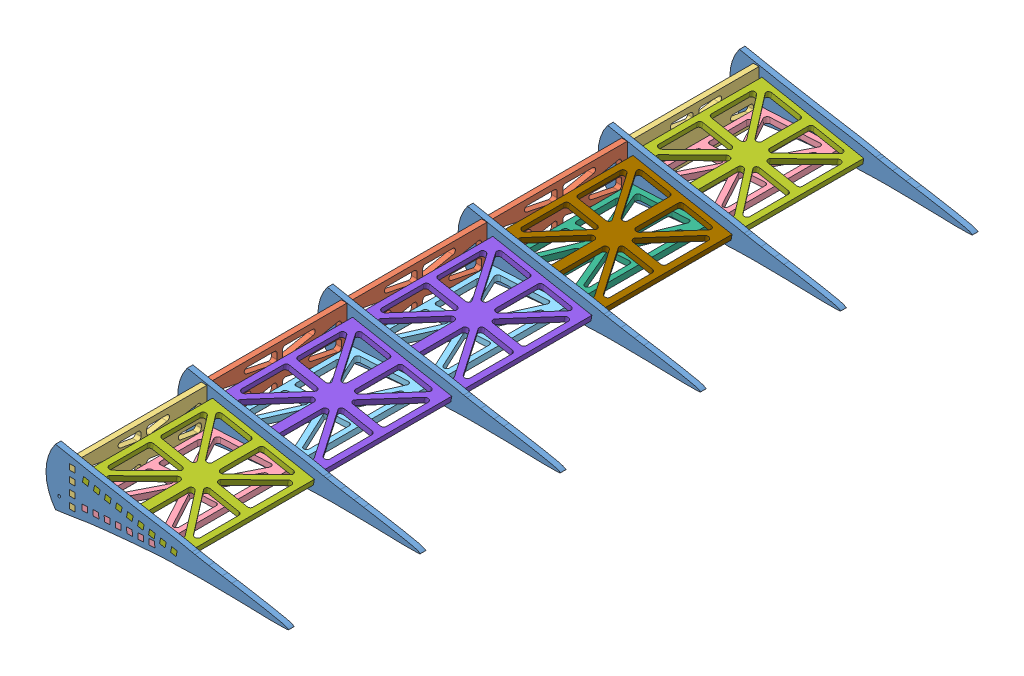
SolidWorks assembly eleron, configuration Default. Lengths in mm.
Overall size (569.01 68.52 550.19).
21 component instances, 9 part files, 60 mates.
Components (placement in the parent):
- eleron_2-1: eleron_2 [Default] at (-99.8109 340.0461 432.4924) size (569.01 68.52 62.19)
- eleron_2-2: eleron_2 [Default] at (-99.8109 340.0461 826.4924) size (569.01 68.52 62.19)
- vertical_eleron_96mm-1: vertical_eleron_96mm [Default] at (316.8476 362.3289 674.4924) x (0 0 -1) z (0 -1 0) size (104 4 35.61)
- eleron_2-3: eleron_2 [Default] at (-99.8109 340.0461 626.4924) size (569.01 68.52 62.19)
- eleron_2-4: eleron_2 [Default] at (-99.8109 340.0461 526.4924) size (569.01 68.52 62.19)
- eleron_2-5: eleron_2 [Default] at (-99.8109 340.0461 920.4924) size (569.01 68.52 62.19)
- eleron_2-6: eleron_2 [Default] at (-99.8109 340.0461 726.4924) size (569.01 68.52 62.19)
- vertical_eleron_90mm-1: vertical_eleron_90mm [Default] at (316.8476 360.3289 902.9685) x (0 0 -1) z (0 -1 0) size (98 4 34.76)
- vertical_eleron_96mm-2: vertical_eleron_96mm [Default] at (316.8476 362.3289 574.4924) x (0 0 -1) z (0 -1 0) size (104 4 35.61)
- vertical_eleron_96mm-3: vertical_eleron_96mm [Default] at (316.8476 362.3289 474.4924) x (0 0 -1) z (0 -1 0) size (104 4 35.61)
- vertical_eleron_90mm-2: vertical_eleron_90mm [Default] at (316.8476 364.3289 446.0162) x (0 0 1) z (0 1 0) size (98 4 34.76)
- orizontala_eleron_90mm_7_gauri-1: orizontala_eleron_90mm_7_gauri [Default] at (332.9244 356.4588 906.0924) x (0 0 -1) z (0.998562 0.053604 0) size (98 4 58)
- orizontala_eleron_96mm_7_gauri-1: orizontala_eleron_96mm_7_gauri [Default] at (361.5332 357.9945 744.2066) x (0 0 1) z (-0.998562 -0.053604 0) size (104 4 56)
- orizontala_eleron_96mm_7_gauri-2: orizontala_eleron_96mm_7_gauri [Default] at (361.5332 357.9945 644.2066) x (0 0 1) z (-0.998562 -0.053604 0) size (104 4 56)
- orizontala_eleron_90mm_7_gauri-2: orizontala_eleron_90mm_7_gauri [Default] at (362.1823 358.0294 442.8924) x (0 0 1) z (-0.998562 -0.053604 0) size (98 4 58)
- orizontala_eleron_96mm_7_gauri_2-1: orizontala_eleron_96mm_7_gauri_2 [Default] at (361.5332 357.9945 544.2066) x (0 0 1) z (-0.998562 -0.053604 0) size (104 4 56)
- orizontala_eleron_90mm_9_gauri-1: orizontala_eleron_90mm_9_gauri [Default] at (333.9983 371.3057 906.0924) x (0 0 -1) z (0.98244 -0.18658 0) size (98 4 74)
- orizontala_eleron_96mm_9_gauri-1: orizontala_eleron_96mm_9_gauri [Default] at (377.8643 362.9749 744.2066) x (0 0 1) z (-0.98244 0.18658 0) size (104 4 72)
- orizontala_eleron_90mm_9_gauri-2: orizontala_eleron_90mm_9_gauri [Default] at (378.5029 362.8536 442.8924) x (0 0 1) z (-0.98244 0.18658 0) size (98 4 74)
- orizontala_eleron_96mm_9_gauri-2: orizontala_eleron_96mm_9_gauri [Default] at (377.8643 362.9749 644.2066) x (0 0 1) z (-0.98244 0.18658 0) size (104 4 72)
- orizontala_eleron_96mm_9_gauri_2-1: orizontala_eleron_96mm_9_gauri_2 [Default] at (334.6369 371.1844 604.7781) x (0 0 -1) z (0.98244 -0.18658 0) size (104 4 72)
Mates (geometry in assembly coordinates):
- Concentric2: concentric aligned: circle of eleron_2-1; circle of eleron_2-2
- Concentric3: concentric aligned: circle of eleron_2-1; circle of eleron_2-3
- Concentric4: concentric aligned: circle of eleron_2-1; circle of eleron_2-4
- Concentric5: concentric aligned: circle of eleron_2-1; circle of eleron_2-5
- Concentric6: concentric aligned: circle of eleron_2-1; circle of eleron_2-6
- Parallel1: parallel aligned: line of eleron_2-5 through (400.3332 336.2444 920.4924) axis (0 1 0); line of eleron_2-6 through (400.3332 336.2444 726.4924) axis (0 1 0)
- Parallel2: parallel aligned: line of eleron_2-5 through (400.3332 336.2444 920.4924) axis (0 1 0); line of eleron_2-2 through (400.3332 336.2444 826.4924) axis (0 1 0)
- Parallel3: parallel aligned: line of eleron_2-5 through (400.3332 336.2444 920.4924) axis (0 1 0); line of eleron_2-3 through (400.3332 336.2444 626.4924) axis (0 1 0)
- Parallel4: parallel aligned: line of eleron_2-5 through (400.3332 336.2444 920.4924) axis (0 1 0); line of eleron_2-4 through (400.3332 336.2444 526.4924) axis (0 1 0)
- Parallel5: parallel aligned: line of eleron_2-5 through (400.3332 336.2444 920.4924) axis (0 1 0); line of eleron_2-1 through (400.3332 336.2444 432.4924) axis (0 1 0)
- Distance1: distance = 90 mm anti-aligned: plane of eleron_2-5 through (-99.8109 340.0461 916.4924) normal (0 0 -1); plane of eleron_2-2 through (-99.8109 340.0461 826.4924) normal (0 0 1)
- Distance2: distance = 96 mm anti-aligned: plane of eleron_2-2 through (-99.8109 340.0461 822.4924) normal (0 0 -1); plane of eleron_2-6 through (-99.8109 340.0461 726.4924) normal (0 0 1)
- Distance3: distance = 96 mm anti-aligned: plane of eleron_2-6 through (-99.8109 340.0461 722.4924) normal (0 0 -1); plane of eleron_2-3 through (-99.8109 340.0461 626.4924) normal (0 0 1)
- Distance4: distance = 96 mm anti-aligned: plane of eleron_2-4 through (-99.8109 340.0461 526.4924) normal (0 0 1); plane of eleron_2-3 through (-99.8109 340.0461 622.4924) normal (0 0 -1)
- Distance5: distance = 90 mm anti-aligned: plane of eleron_2-4 through (-99.8109 340.0461 522.4924) normal (0 0 -1); plane of eleron_2-1 through (-99.8109 340.0461 432.4924) normal (0 0 1)
- Coincident23: coincident aligned: plane of eleron_2-5 through (-99.8109 340.0461 920.4924) normal (0 0 1); plane of vertical_eleron_90mm-1 through (312.8476 368.3289 920.4924) normal (0 0 1)
- Coincident24: coincident anti-aligned: plane of eleron_2-5 through (312.8476 376.3289 916.4924) normal (0 -1 0); plane of vertical_eleron_90mm-1 through (312.8476 376.3289 916.4924) normal (0 1 0)
- Coincident25: coincident anti-aligned: plane of eleron_2-5 through (316.8476 376.3289 916.4924) normal (-1 0 0); plane of vertical_eleron_90mm-1 through (316.8476 360.3289 902.9685) normal (1 0 0)
- Coincident26: coincident anti-aligned: plane of eleron_2-2 through (-99.8109 340.0461 822.4924) normal (0 0 -1); plane of vertical_eleron_96mm-1 through (312.8476 380.5589 822.4924) normal (0 0 1)
- Coincident27: coincident anti-aligned: plane of eleron_2-2 through (312.8476 348.3289 822.4924) normal (0 1 0); plane of vertical_eleron_96mm-1 through (312.8476 348.3289 826.4924) normal (0 -1 0)
- Coincident28: coincident anti-aligned: plane of eleron_2-2 through (316.8476 368.3289 822.4924) normal (-1 0 0); plane of vertical_eleron_96mm-1 through (316.8476 362.3289 674.4924) normal (1 0 0)
- Coincident29: coincident anti-aligned: plane of eleron_2-6 through (316.8476 352.3289 722.4924) normal (-1 0 0); plane of vertical_eleron_96mm-2 through (316.8476 362.3289 574.4924) normal (1 0 0)
- Coincident30: coincident anti-aligned: plane of eleron_2-6 through (312.8476 348.3289 722.4924) normal (0 1 0); plane of vertical_eleron_96mm-2 through (312.8476 348.3289 726.4924) normal (0 -1 0)
- Coincident31: coincident anti-aligned: plane of eleron_2-6 through (-99.8109 340.0461 722.4924) normal (0 0 -1); plane of vertical_eleron_96mm-2 through (312.8476 380.5589 722.4924) normal (0 0 1)
- Coincident32: coincident anti-aligned: plane of eleron_2-3 through (-99.8109 340.0461 622.4924) normal (0 0 -1); plane of vertical_eleron_96mm-3 through (312.8476 380.5589 622.4924) normal (0 0 1)
- Coincident33: coincident anti-aligned: plane of eleron_2-3 through (312.8476 348.3289 622.4924) normal (0 1 0); plane of vertical_eleron_96mm-3 through (312.8476 348.3289 626.4924) normal (0 -1 0)
- Coincident34: coincident anti-aligned: plane of eleron_2-3 through (316.8476 352.3289 622.4924) normal (-1 0 0); plane of vertical_eleron_96mm-3 through (316.8476 362.3289 474.4924) normal (1 0 0)
- Coincident35: coincident anti-aligned: plane of eleron_2-4 through (-99.8109 340.0461 522.4924) normal (0 0 -1); plane of vertical_eleron_90mm-2 through (312.8476 352.3289 522.4924) normal (0 0 1)
- Coincident36: coincident anti-aligned: plane of eleron_2-4 through (312.8476 348.3289 522.4924) normal (0 1 0); plane of vertical_eleron_90mm-2 through (312.8476 348.3289 522.4924) normal (0 -1 0)
- Coincident37: coincident anti-aligned: plane of eleron_2-4 through (316.8476 368.3289 522.4924) normal (-1 0 0); plane of vertical_eleron_90mm-2 through (316.8476 364.3289 446.0162) normal (1 0 0)
- Coincident38: coincident anti-aligned: plane of eleron_2-5 through (-99.8109 340.0461 916.4924) normal (0 0 -1); plane of orizontala_eleron_90mm_7_gauri-1 through (365.7419 354.2147 916.4924) normal (0 0 1)
- Coincident39: coincident anti-aligned: plane of eleron_2-5 through (373.516 358.6378 916.4924) normal (-0.998562 -0.053604 0); plane of orizontala_eleron_90mm_7_gauri-1 through (373.7304 354.6435 920.4924) normal (0.998562 0.053604 0)
- Coincident40: coincident anti-aligned: plane of eleron_2-5 through (369.5217 358.4234 916.4924) normal (0.053604 -0.998562 0); plane of orizontala_eleron_90mm_7_gauri-1 through (332.9244 356.4588 906.0924) normal (-0.053604 0.998562 0)
- Coincident41: coincident anti-aligned: plane of eleron_2-2 through (-99.8109 340.0461 822.4924) normal (0 0 -1); plane of orizontala_eleron_96mm_7_gauri-1 through (319.808 351.7489 822.4924) normal (0 0 1)
- Coincident42: coincident anti-aligned: plane of eleron_2-2 through (361.5332 357.9945 822.4924) normal (0.053604 -0.998562 0); plane of orizontala_eleron_96mm_7_gauri-1 through (361.5332 357.9945 744.2066) normal (-0.053604 0.998562 0)
- Coincident43: coincident anti-aligned: plane of eleron_2-2 through (365.5275 358.209 822.4924) normal (-0.998562 -0.053604 0); plane of orizontala_eleron_96mm_7_gauri-1 through (365.7419 354.2147 822.4924) normal (0.998562 0.053604 0)
- Coincident44: coincident anti-aligned: plane of eleron_2-6 through (-99.8109 340.0461 722.4924) normal (0 0 -1); plane of orizontala_eleron_96mm_7_gauri-2 through (375.7275 354.7507 722.4924) normal (0 0 1)
- Coincident45: coincident anti-aligned: plane of eleron_2-6 through (361.5332 357.9945 722.4924) normal (0.053604 -0.998562 0); plane of orizontala_eleron_96mm_7_gauri-2 through (361.5332 357.9945 644.2066) normal (-0.053604 0.998562 0)
- Coincident46: coincident anti-aligned: plane of eleron_2-6 through (365.5275 358.209 722.4924) normal (-0.998562 -0.053604 0); plane of orizontala_eleron_96mm_7_gauri-2 through (365.7419 354.2147 722.4924) normal (0.998562 0.053604 0)
- Coincident51: coincident anti-aligned: plane of eleron_2-3 through (-99.8109 340.0461 622.4924) normal (0 0 -1); plane of orizontala_eleron_96mm_7_gauri_2-1 through (319.808 351.7489 622.4924) normal (0 0 1)
- Coincident52: coincident anti-aligned: plane of eleron_2-3 through (365.5275 358.209 622.4924) normal (-0.998562 -0.053604 0); plane of orizontala_eleron_96mm_7_gauri_2-1 through (365.7419 354.2147 622.4924) normal (0.998562 0.053604 0)
- Coincident54: coincident anti-aligned: plane of eleron_2-3 through (361.5332 357.9945 622.4924) normal (0.053604 -0.998562 0); plane of orizontala_eleron_96mm_7_gauri_2-1 through (361.5332 357.9945 544.2066) normal (-0.053604 0.998562 0)
- Coincident55: coincident anti-aligned: plane of eleron_2-4 through (337.5677 356.708 522.4924) normal (0.053604 -0.998562 0); plane of orizontala_eleron_90mm_7_gauri-2 through (362.1823 358.0294 442.8924) normal (-0.053604 0.998562 0)
- Coincident56: coincident anti-aligned: plane of eleron_2-4 through (-99.8109 340.0461 522.4924) normal (0 0 -1); plane of orizontala_eleron_90mm_7_gauri-2 through (369.7362 354.4291 522.4924) normal (0 0 1)
- Coincident57: coincident anti-aligned: plane of eleron_2-4 through (321.8052 351.8561 522.4924) normal (0.998562 0.053604 0); plane of orizontala_eleron_90mm_7_gauri-2 through (321.8052 351.8561 526.4924) normal (-0.998562 -0.053604 0)
- Coincident58: coincident anti-aligned: plane of eleron_2-5 through (-99.8109 340.0461 916.4924) normal (0 0 -1); plane of orizontala_eleron_90mm_9_gauri-1 through (326.0311 368.7473 916.4924) normal (0 0 1)
- Coincident59: coincident anti-aligned: plane of eleron_2-5 through (388.9072 356.8062 916.4924) normal (-0.98244 0.18658 0); plane of orizontala_eleron_90mm_9_gauri-1 through (388.9072 356.8062 920.4924) normal (0.98244 -0.18658 0)
- Coincident60: coincident anti-aligned: plane of eleron_2-5 through (389.6536 360.7359 916.4924) normal (-0.18658 -0.98244 0); plane of orizontala_eleron_90mm_9_gauri-1 through (333.9983 371.3057 906.0924) normal (0.18658 0.98244 0)
- Coincident61: coincident anti-aligned: plane of eleron_2-2 through (-99.8109 340.0461 822.4924) normal (0 0 -1); plane of orizontala_eleron_96mm_9_gauri-1 through (345.6799 365.0157 822.4924) normal (0 0 1)
- Coincident62: coincident anti-aligned: plane of eleron_2-2 through (381.0477 358.2988 822.4924) normal (-0.98244 0.18658 0); plane of orizontala_eleron_96mm_9_gauri-1 through (381.0477 358.2988 822.4924) normal (0.98244 -0.18658 0)
- Coincident63: coincident anti-aligned: plane of eleron_2-2 through (381.794 362.2286 822.4924) normal (-0.18658 -0.98244 0); plane of orizontala_eleron_96mm_9_gauri-1 through (377.8643 362.9749 744.2066) normal (0.18658 0.98244 0)
- Coincident67: coincident anti-aligned: plane of eleron_2-1 through (-99.8109 340.0461 432.4924) normal (0 0 1); plane of orizontala_eleron_90mm_9_gauri-2 through (322.1013 369.4936 432.4924) normal (0 0 -1)
- Coincident68: coincident anti-aligned: plane of eleron_2-1 through (388.9072 356.8062 428.4924) normal (-0.98244 0.18658 0); plane of orizontala_eleron_90mm_9_gauri-2 through (388.9072 356.8062 432.4924) normal (0.98244 -0.18658 0)
- Coincident69: coincident anti-aligned: plane of eleron_2-1 through (389.6536 360.7359 428.4924) normal (-0.18658 -0.98244 0); plane of orizontala_eleron_90mm_9_gauri-2 through (378.5029 362.8536 442.8924) normal (0.18658 0.98244 0)
- Coincident70: coincident anti-aligned: plane of eleron_2-6 through (381.794 362.2286 722.4924) normal (-0.18658 -0.98244 0); plane of orizontala_eleron_96mm_9_gauri-2 through (377.8643 362.9749 644.2066) normal (0.18658 0.98244 0)
- Coincident73: coincident anti-aligned: plane of eleron_2-6 through (-99.8109 340.0461 722.4924) normal (0 0 -1); plane of orizontala_eleron_96mm_9_gauri-2 through (361.3989 362.0304 722.4924) normal (0 0 1)
- Coincident74: coincident anti-aligned: plane of eleron_2-6 through (381.0477 358.2988 722.4924) normal (-0.98244 0.18658 0); plane of orizontala_eleron_96mm_9_gauri-2 through (381.0477 358.2988 722.4924) normal (0.98244 -0.18658 0)
- Coincident75: coincident anti-aligned: plane of eleron_2-3 through (381.794 362.2286 622.4924) normal (-0.18658 -0.98244 0); plane of orizontala_eleron_96mm_9_gauri_2-1 through (334.6369 371.1844 604.7781) normal (0.18658 0.98244 0)
- Coincident76: coincident anti-aligned: plane of eleron_2-3 through (-99.8109 340.0461 622.4924) normal (0 0 -1); plane of orizontala_eleron_96mm_9_gauri_2-1 through (365.3287 361.2841 622.4924) normal (0 0 1)
- Coincident77: coincident anti-aligned: plane of eleron_2-3 through (330.7072 371.9307 622.4924) normal (0.98244 -0.18658 0); plane of orizontala_eleron_96mm_9_gauri_2-1 through (329.9608 368.001 622.4924) normal (-0.98244 0.18658 0)
